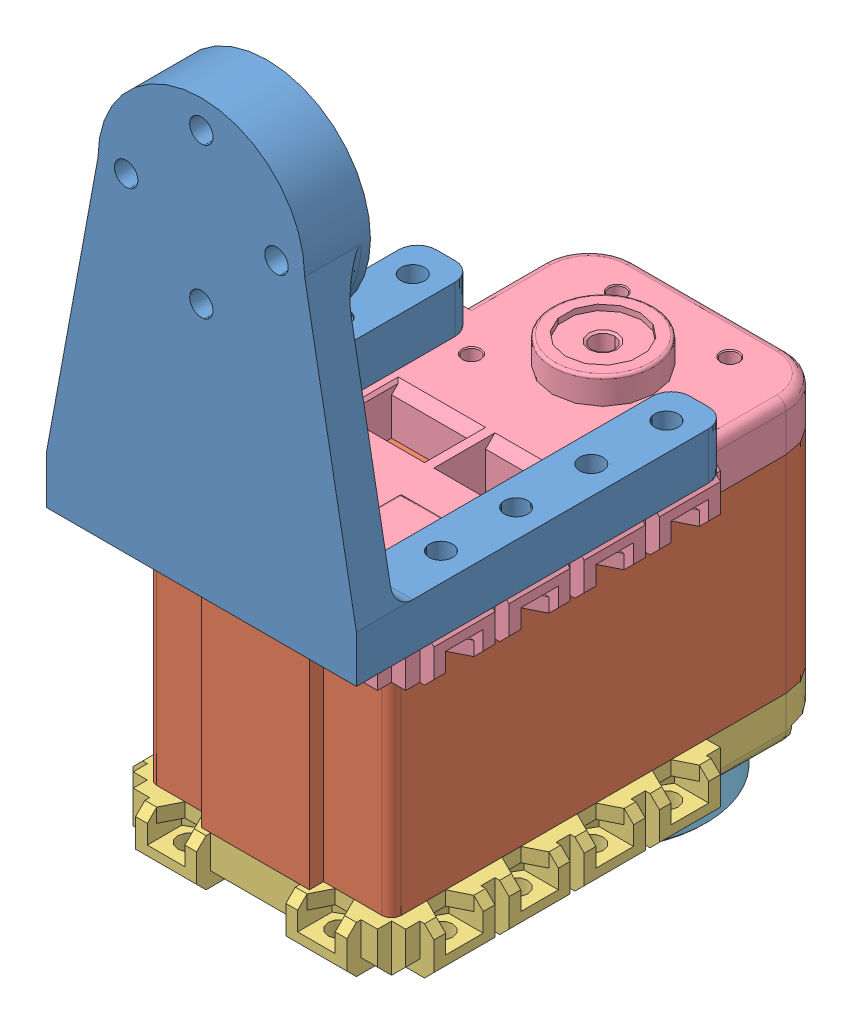
SolidWorks assembly ass_support_couderV3B, configuration Défaut. Lengths in mm.
Overall size (33 83.55 54.25).
11 component instances, 7 part files, 3 mates.
Components (placement in the parent):
- support_couderV3B-1: support_couderV3B [Défaut] at (-1.9847 8.2315 53.25) size (33 46 39.5)
- AX-12A-1: AX-12A [Default] at (-1.9847 -42.7685 17.5) x (0 0 1) z (0 -1 0) size (50 32 40.55)
  - AX-12A-01-1: AX-12A-01 [Default] at origin size (48.5 26 22)
  - AX-12A-02-1: AX-12A-02 [Default] at (0 0 13.5) size (50 32 8)
  - AX-12A-03-1: AX-12A-03 [Default] at (0 0 -13.5) x (1 0 0) z (0 0 -1) size (50 32 8)
  - AX-12A-04-1: AX-12A-04 [Default] at (0 0 21) size (22 22 6.7)
  - SetScrew-5: SetScrew [Default] at (33 10.4 14.5) x (0.31498 0.949098 0) z (0 0 -1) size (3.3 3.3 29.44)
  - SetScrew-6: SetScrew [Default] at (-9 9.25 14.5) x (0.31498 0.949098 0) z (0 0 -1) size (3.3 3.3 29.44)
  - SetScrew-7: SetScrew [Default] at (-9 -9.25 14.5) x (-0.958559 0.284893 0) z (0 0 -1) size (3.3 3.3 29.44)
  - SetScrew-8: SetScrew [Default] at (33 -10.4 14.5) x (0.31498 0.949098 0) z (0 0 -1) size (3.3 3.3 29.44)
  - pan head cross recess screw_iso-1: pan head cross recess screw_iso [ISO 7045 - M2.5 x 8 - Z --- 8C] at (0 0 21.6) x (0 0 -1) z (1 0 0) size (10.05 5 5)
Mates (geometry in assembly coordinates):
- Coaxiale1: concentric aligned: cylinder of support_couderV3B-1 through (-15.4847 -26.7685 48.25) axis (0 1 0) radius 1.25; cylinder of AX-12A-1/AX-12A-03-1 through (-15.4847 -31.7695 48.25) axis (0 1 0) radius 1.25
- Coaxiale2: concentric aligned: cylinder of support_couderV3B-1 through (-15.4847 -26.7685 24.25) axis (0 1 0) radius 1.25; cylinder of AX-12A-1/AX-12A-03-1 through (-15.4847 -31.7695 24.25) axis (0 1 0) radius 1.25
- Coïncidente1: coincident anti-aligned: plane of support_couderV3B-1 through (9.0153 -26.7685 56.25) normal (0 -1 0); plane of AX-12A-1/AX-12A-03-1 through (-1.9847 -26.7685 17.5) normal (0 1 0)
